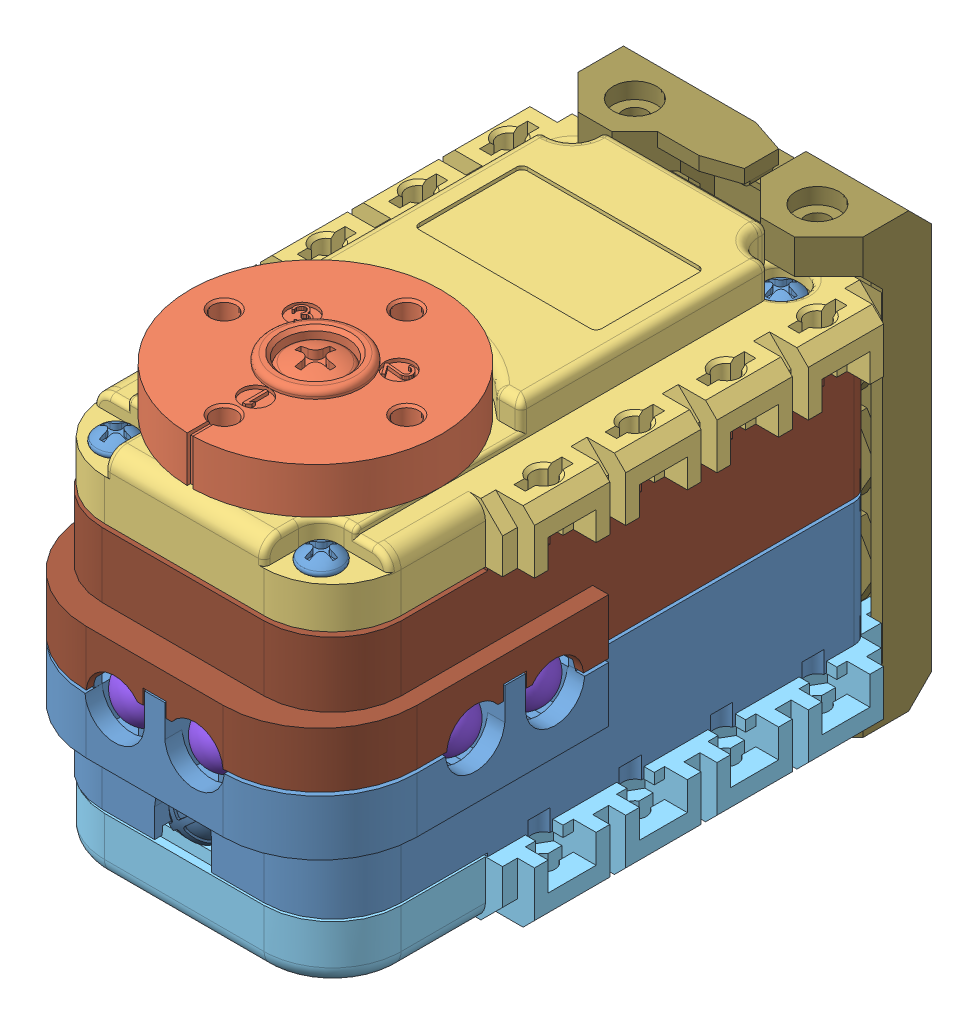
SolidWorks assembly AX-S11, configuration Défaut. Lengths in mm.
Overall size (32 40.7 55.63).
13 component instances, 12 part files, 3 mates.
Components (placement in the parent):
- 9_ALL_COMPONENTS-1-1: 9_ALL_COMPONENTS-1 [Défaut] at origin size (29.07 30.77 51.23)
- 9_ALL_COMPONENTS_1-1-1: 9_ALL_COMPONENTS_1-1 [Défaut] at origin size (22 9.8 22)
- AX123_CASE-T_-1-1: AX123_CASE-T_-1 [Défaut] at origin size (32 9.94 50)
- AX123_LED-COVER_-1-1: AX123_LED-COVER_-1 [Défaut] at origin size (10.71 7.51 16.69)
- DX124_CASE-B_-1-1: DX124_CASE-B_-1 [Défaut] at origin size (32 11.7 50)
- DX124_PCB_SENSOR__-1-1: DX124_PCB_SENSOR__-1 [Défaut] at origin size (28.14 17.2 47.1)
  - 099990987__-1-1: 099990987__-1 [Défaut] at origin size (9.9 9.41 4.9)
  - 099990987___1-1-1: 099990987___1-1 [Défaut] at origin size (9.9 9.41 4.9)
  - 9_ALL_COMPONENTS_2-1-1: 9_ALL_COMPONENTS_2-1 [Défaut] at origin size (28.14 10.9 23)
  - DX124_PCB_SENSOR___1-1-1: DX124_PCB_SENSOR___1-1 [Défaut] at origin size (22.1 1.6 43)
  - REMOCON_PREAMP___-1-1: REMOCON_PREAMP___-1 [Défaut] at origin size (6.8 9.25 10.35)
- DX124_SENSOR-T__-1-1: DX124_SENSOR-T__-1 [Défaut] at origin size (29 18.9 51.22)
- F3-1: F3 [Défaut] at (0 -11 -41.5) x (1 0 0) z (0 -1 0) size (25 9 38)
Mates (geometry in assembly coordinates):
- Coaxiale1: concentric: cylinder of AX123_CASE-T_-1-1 through (8 2.5 -36) axis (0 1 0) radius 1; cylinder of F3-1 through (8 8 -36) axis (0 1 0) radius 1.05
- Coïncidente1: coincident: plane of AX123_CASE-T_-1-1 through (-15.6 5 -38.37) normal (0 1 0); plane of F3-1 through (3.5 5 -39.5) normal (0 -1 0)
- Parallèle1: parallel aligned: plane of AX123_CASE-T_-1-1 through (-16 4.0821 -2.588) normal (-1 0 0); plane of F3-1 through (-12.5 8.76 -41.62) normal (-1 0 0)
